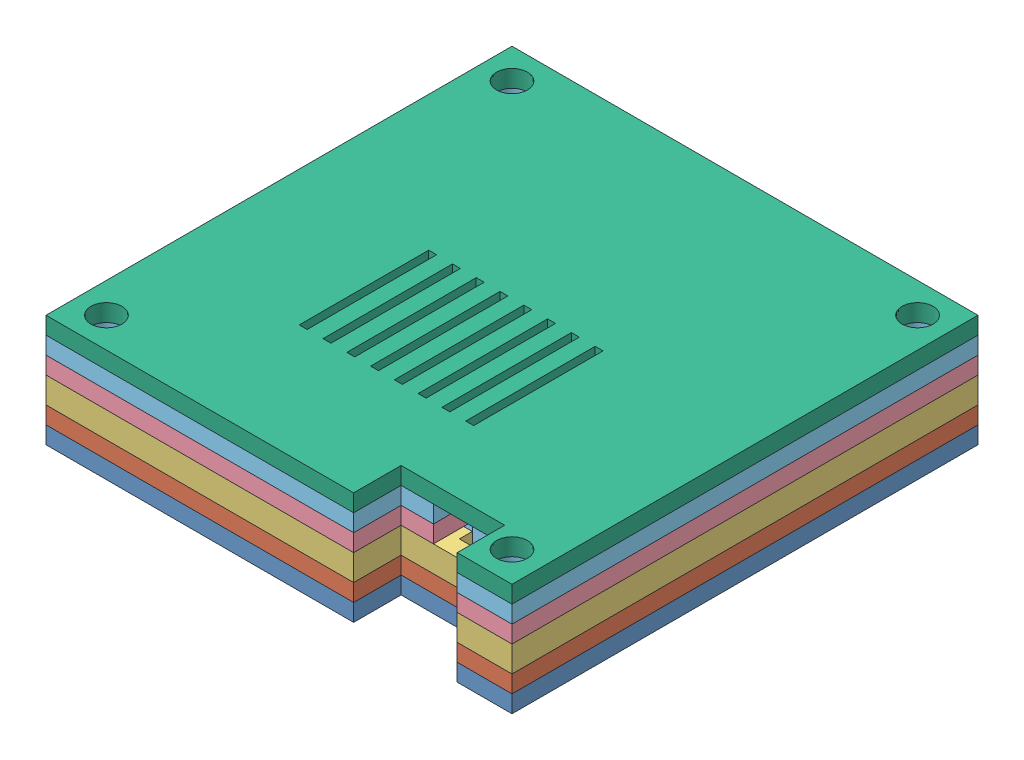
SolidWorks assembly 装配体, configuration 默认. Lengths in mm.
Overall size (54 13 54).
6 component instances, 6 part files, 4 mates.
Components (placement in the parent):
- 下盖3-2: 下盖3 [Default] at (0.6893 6.039 54.022) size (54 2 54)
- 下盖2-2: 下盖2 [Default] at (0.6893 8.039 54.022) size (54 2 54)
- 下盖1-2: 下盖1 [Default] at (0.6893 10.039 54.022) size (54 3 54)
- 上盖1-2: 上盖1 [Default] at (0.6893 13.039 54.022) size (54 2 54)
- 上盖2-2: 上盖2 [Default] at (0.6893 15.039 54.022) size (54 2 54)
- 上盖3-2: 上盖3 [Default] at (0.6893 17.039 54.022) size (54 2 54)
Mates (geometry in assembly coordinates):
- 重合5: coincident aligned: plane of 下盖3-2 through (0.6893 8.039 81.022) normal (0 0 1); plane of 下盖2-2 through (0.6893 10.039 81.022) normal (0 0 1)
- 重合7: coincident aligned: plane of 下盖3-2 through (-26.3107 8.039 54.022) normal (-1 0 0); plane of 下盖2-2 through (-26.3107 10.039 54.022) normal (-1 0 0)
- 重合8: coincident anti-aligned: plane of 下盖3-2 through (0.6893 8.039 54.022) normal (0 1 0); plane of 下盖2-2 through (0.6893 8.039 54.022) normal (0 -1 0)
- 重合36: coincident anti-aligned: plane of 下盖2-2 through (0.6893 10.039 54.022) normal (0 1 0); plane of 下盖1-2 through (0.6893 10.039 54.022) normal (0 -1 0)
